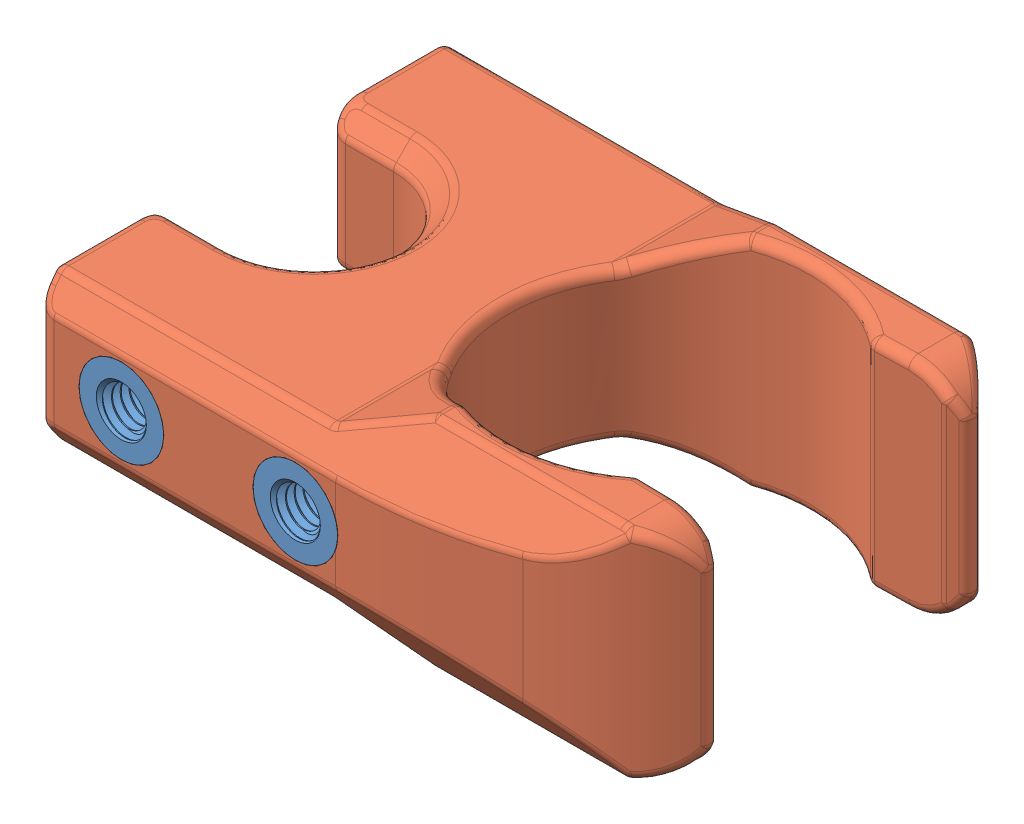
SolidWorks assembly 20021-003_arm-clip, configuration Default. Lengths in mm.
Overall size (30.85 11.33 22.06).
5 component instances, 2 part files, 0 mates.
Components (placement in the parent):
- 94180A321_1-1: 94180A321_1 [Default] at (-17.8646 0 11) x (1 0 0) z (0 -1 0) size (4.37 3.46 4.37)
- 94180A321_1-2: 94180A321_1 [Default] at (-8.8476 0 11) x (1 0 0) z (0 -1 0) size (4.37 3.46 4.37)
- 94180A321_1-3: 94180A321_1 [Default] at (-8.8476 0 -11) x (1 0 0) z (0 1 0) size (4.37 3.46 4.37)
- 94180A321_1-4: 94180A321_1 [Default] at (-17.8646 0 -11) x (1 0 0) z (0 1 0) size (4.37 3.46 4.37)
- 20021-003_arm-clip v2-1: 20021-003_arm-clip v2 [Default] at (-0.993 0 0) size (30.85 11.33 22.03)
